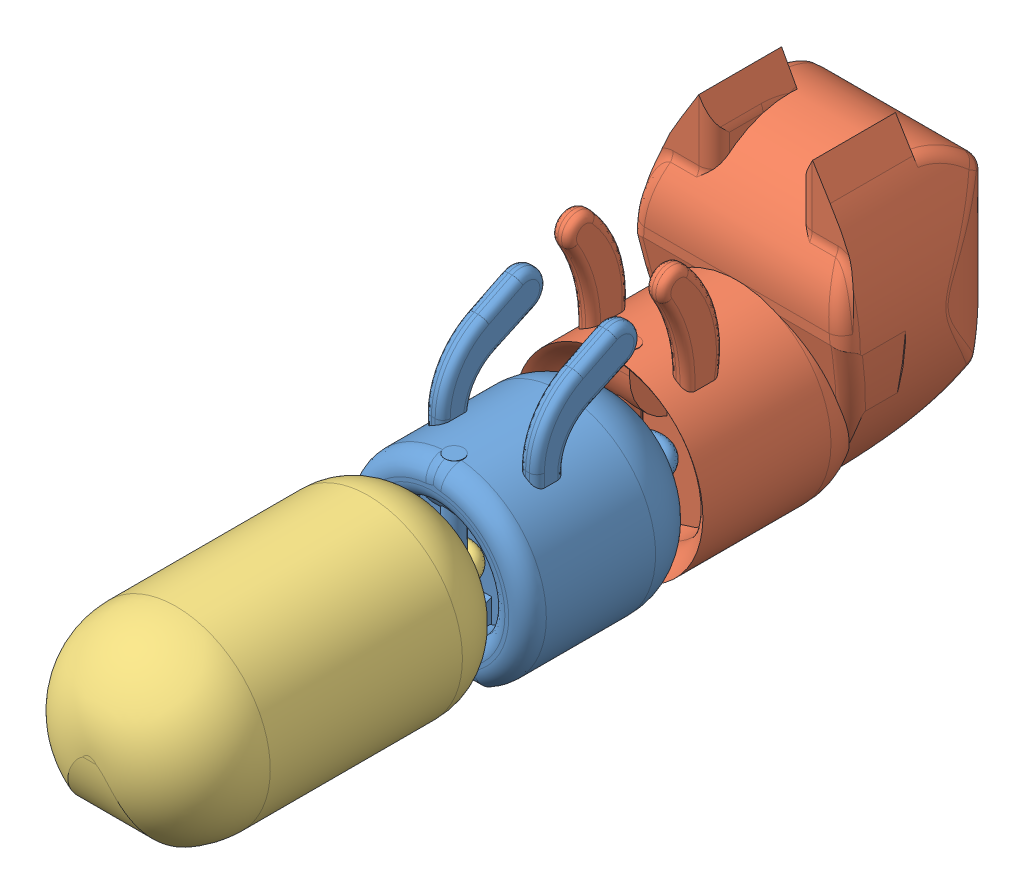
SolidWorks assembly Ensamblaje1, configuration Predeterminado. Lengths in mm.
Overall size (58.31 80.32 223.63).
3 component instances, 3 part files, 4 mates.
Components (placement in the parent):
- Panza-1: Panza [Predeterminado] at (0.3684 -0.7367 63) size (50 68.78 61.5)
- cabeza-1: cabeza [Predeterminado] at (-1.8901 -0.7367 14.1868) size (58.31 80.32 85.77)
- Tracero-1: Tracero [Predeterminado] at (-1.3199 -0.7367 112.5849) size (50 47 101.5)
Mates (geometry in assembly coordinates):
- Coincidente11: coincident aligned: plane of Panza-1 through (0.3684 -22.7367 63) normal (0 -1 0); plane of cabeza-1 through (-1.8901 -22.7367 14.1868) normal (0 -1 0)
- Coincidente12: coincident: cylinder of assembly; point of Panza-1; cylinder of cabeza-1 through (-1.8901 24.2633 58.6778) axis (0 -1 0) radius 2.5
- Coincidente13: coincident: plane of Panza-1 through (0.3684 -22.7367 63) normal (0 -1 0); plane of Tracero-1 through (-1.3199 -22.7367 112.5849) normal (0 -1 0)
- Coincidente14: coincident: cylinder of Panza-1 through (0.3684 24.2633 107.491) axis (0 -1 0) radius 2.5
